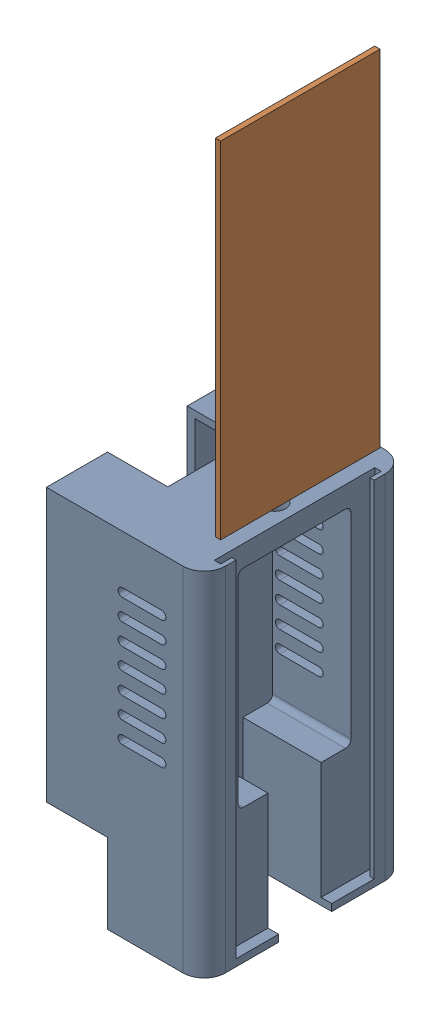
SolidWorks assembly Adapter_V2, configuration Default. Lengths in mm.
Overall size (37.72 171.49 48.26).
2 component instances, 2 part files, 3 mates.
Components (placement in the parent):
- Adapter_Case_V2-1: Adapter_Case_V2 [Default] at origin size (37.72 84.21 48.26)
- Adapter_Cover-1: Adapter_Cover [Default] at (36.449 4.729 -3.302) x (0 0 1) z (-1 0 0) size (38.1 82.55 1.27)
Mates (geometry in assembly coordinates):
- Coincident1: coincident anti-aligned: plane of Adapter_Case_V2-1 through (35.179 -82.55 -41.402) normal (1 0 0); plane of Adapter_Cover-1 through (35.179 4.729 -3.302) normal (-1 0 0)
- Coincident4: coincident: plane of Adapter_Case_V2-1 through (0 -82.55 0) normal (0 1 0); plane of Adapter_Cover-1 through (35.179 -82.55 -3.302) normal (0 -1 0)
- Coincident5: coincident anti-aligned: plane of Adapter_Case_V2-1 through (36.703 -82.55 -41.402) normal (0 0 1); plane of Adapter_Cover-1 through (35.179 4.729 -41.402) normal (0 0 -1)
